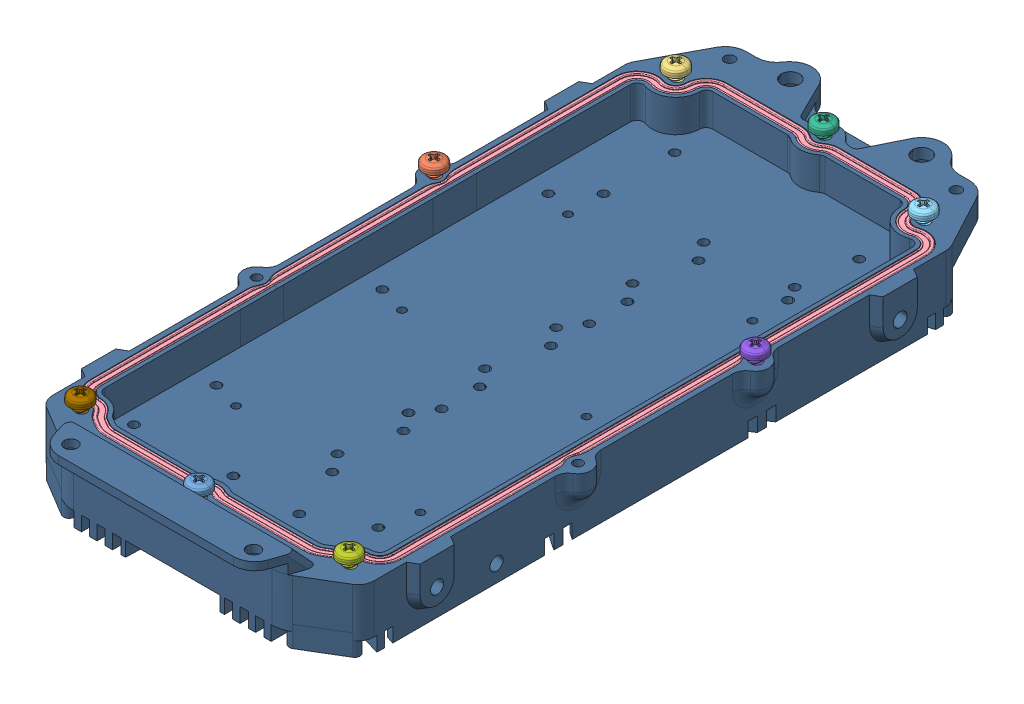
SolidWorks assembly 1101组装, configuration 默认. Lengths in mm.
Overall size (134.57 31.12 277.52).
12 component instances, 11 part files, 0 mates.
Components (placement in the parent):
- 1101上盖组装-1: 1101上盖组装 [默认] at (-5.6296 -9.373 287.2543) x (1 0 0) z (0 1 0) size (132 248.03 42.19)
  - 复件 HOUGAI^1101上盖组装-1: 复件 HOUGAI^1101上盖组装 [默认] at origin size (132 248.03 33.79) (hidden, virtual)
  - 复件 97100^1101上盖组装-1: 复件 97100^1101上盖组装 [默认] at origin size (8.46 8.46 14.97) (virtual)
  - 复件 97500^1101上盖组装-1: 复件 97500^1101上盖组装 [默认] at origin size (8.46 8.46 14.97) (virtual)
  - 复件 97600^1101上盖组装-1: 复件 97600^1101上盖组装 [默认] at origin size (8.46 8.46 14.97) (virtual)
  - 复件 99400^1101上盖组装-1: 复件 99400^1101上盖组装 [默认] at origin size (117.8 233.8 2.53) (virtual)
  - 复件 97700^1101上盖组装-1: 复件 97700^1101上盖组装 [默认] at origin size (8.46 8.46 14.97) (virtual)
  - 复件 96800^1101上盖组装-1: 复件 96800^1101上盖组装 [默认] at origin size (8.46 8.46 13.63) (virtual)
  - 复件 97200^1101上盖组装-1: 复件 97200^1101上盖组装 [默认] at origin size (8.46 8.46 14.97) (virtual)
  - 复件 97400^1101上盖组装-1: 复件 97400^1101上盖组装 [默认] at origin size (8.46 8.46 14.97) (virtual)
  - 复件 97000^1101上盖组装-1: 复件 97000^1101上盖组装 [默认] at origin size (8.46 8.46 14.97) (virtual)
- 1101散热器-1: 1101散热器 [默认] at (-5.6296 -9.373 287.2543) x (1 0 0) z (0 1 0) size (134.57 277.52 31.12)
